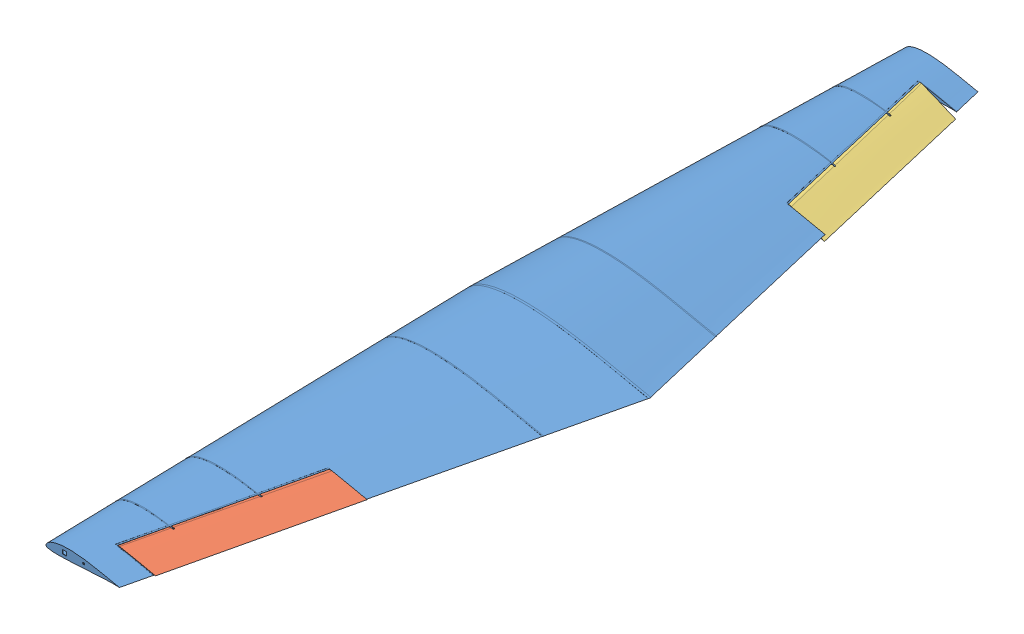
SolidWorks assembly EAS4710 Wing Assembly TD, configuration Default. Lengths in mm.
Overall size (362.97 76.96 1524).
3 component instances, 3 part files, 4 mates.
Components (placement in the parent):
- InitialWing ribbed V4 -1: InitialWing ribbed V4  [Default] at (491.1762 827.4063 1092.5073) size (362.97 69.6 1524)
- EAS4710 Left Aileron v2 TD-1: EAS4710 Left Aileron v2 TD [Default] at (657.6424 832.1339 1499.3883) x (0.999984 -0.005697 -0.000408) z (0.00041 0.000336 1) size (144.04 16.57 304.82)
- EAS4710 Right Aileron v2 TD-1: EAS4710 Right Aileron v2 TD [Default] at (657.2972 832.1577 685.3718) x (0.983887 -0.178786 0.001365) z (0.00582 0.039655 0.999196) size (144.04 16.37 304.82)
Mates (geometry in assembly coordinates):
- Coincident1: coincident anti-aligned: line of InitialWing ribbed V4 -1 through (633.3608 833.2699 1602.5073) axis (-0.229098 -0.003011 0.973399); line of EAS4710 Left Aileron v2 TD-1 through (585.8864 832.646 1804.2176) axis (0.229098 0.003011 -0.973399)
- Coincident2: coincident aligned: line of InitialWing ribbed V4 -1 through (603.9409 832.8833 457.5073) axis (0.229098 0.003011 0.973399); line of EAS4710 Right Aileron v2 TD-1 through (585.8691 832.6457 380.7234) axis (0.229098 0.003011 0.973399)
- Coincident3: coincident: plane of InitialWing ribbed V4 -1 through (601.4702 832.8771 1729.5073) normal (0 0 1); point of EAS4710 Left Aileron v2 TD-1
- Coincident4: coincident: plane of InitialWing ribbed V4 -1 through (631.3608 833.2699 582.5073) normal (0 0 -1); point of EAS4710 Right Aileron v2 TD-1
